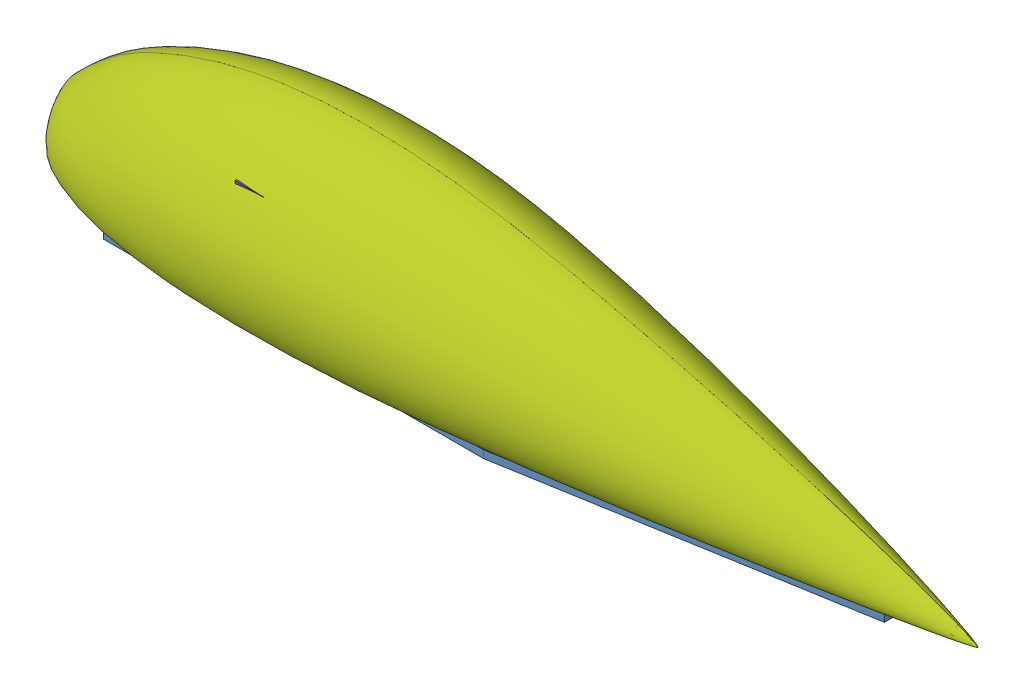
SolidWorks assembly full_vehicle, configuration Default. Lengths in mm.
Overall size (6096.03 1166.77 1555.25).
27 component instances, 15 part files, 32 mates.
Components (placement in the parent):
- sledFrame_003_rw-1: sledFrame_003_rw [Default] at (-4891.4665 1903.7696 4433.3238) size (5588 50.8 1016)
- drive_assembly-1: drive_assembly [Default] at (-3341.0425 1915.3862 4244.1915) x (0 0 1) z (-1 0 0) size (346.08 495.3 1111.25)
  - motor-1: motor [Default] at (4.9823 194.7584 300.6208) size (114.3 330.2 254)
  - drive_wheel-1: drive_wheel [Default] at (189.1323 143.9584 -16.8792) x (0 0 -1) z (1 0 0) size (304.8 304.8 101.6)
  - vertical_stability-1: vertical_stability [Default] at (189.1323 -124.9768 -16.8792) size (165.1 348.85 530.75)
  - drive_wheel-2: drive_wheel [Default] at (189.1323 143.9584 618.1208) x (0 0 1) z (-1 0 0) size (304.8 304.8 101.6)
  - vertical_stability-2: vertical_stability [Default] at (189.1323 -124.9768 618.1208) x (-1 0 0) z (0 0 -1) size (165.1 348.85 530.75)
  - Part1^drive_assembly-1: Part1^drive_assembly [Default] at (84.3573 143.9584 -16.8792) size (12.7 192.09 339.73) (virtual)
  - Part1^drive_assembly-2: Part1^drive_assembly [Default] at (281.2073 143.9584 -16.8792) size (12.7 192.09 339.73) (virtual)
  - Part1^drive_assembly-3: Part1^drive_assembly [Default] at (84.3573 143.9584 618.1208) size (12.7 192.09 339.73) (virtual)
  - Part1^drive_assembly-4: Part1^drive_assembly [Default] at (281.2073 143.9584 618.1208) size (12.7 192.09 339.73) (virtual)
- battery_pack-1: battery_pack [Default] at (-3018.7283 2021.2446 4823.2138) x (0 0 -1) z (1 0 0) size (134.62 152.4 1325.88)
- battery_pack-2: battery_pack [Default] at (-3018.7283 2021.2446 4043.4338) x (0 0 1) z (-1 0 0) size (134.62 152.4 1325.88)
- Body_006_rw-1: Body_006_rw [Default] at (-5653.4665 1954.5696 4433.3238) x (1 0 0.000021) z (-0.000021 0 1) size (6096 981.34 1555.12)
- radiator-1: radiator [Default] at (-3872.1683 2287.9446 3998.3488) x (-1 0 0) z (0 0 1) size (381 685.8 44.45)
- horizontal_stability-1: horizontal_stability [Default] at (-2876.2243 1919.6446 4433.3238) x (0 0 -1) z (1 0 0) size (307.09 115.06 127)
- horizontal_stability-2: horizontal_stability [Default] at (-4311.8611 1919.6446 4433.3238) x (0 0 -1) z (1 0 0) size (307.09 115.06 127)
- friction_brake-1: friction_brake [Default] at (-4777.1665 1901.7122 4404.7488) x (0 0 -1) z (1 0 0) size (107.95 142.42 127)
- friction_brake-2: friction_brake [Default] at (-4777.1665 1901.7122 4461.8988) x (0 0 1) z (-1 0 0) size (107.95 142.42 127)
- friction_brake-3: friction_brake [Default] at (-2451.0383 1901.7122 4404.7488) x (0 0 -1) z (1 0 0) size (107.95 142.42 127)
- friction_brake-4: friction_brake [Default] at (-2451.0383 1901.7122 4461.8988) x (0 0 1) z (-1 0 0) size (107.95 142.42 127)
- air_tank-1: air_tank [Default] at (-3359.7769 2030.7696 4686.1159) x (0 0 -1) z (1 0 0) size (152.4 152.4 279.4)
- compressor-1: compressor [Default] at (-2979.22 2008.5446 4702.3337) x (0 0 -1) z (1 0 0) size (127 127 254)
- radiator-2: radiator [Default] at (-3872.1683 2287.9446 4868.2988) x (-1 0 0) z (0 0 1) size (381 685.8 44.45)
- male95_scaled-1: male95_scaled [Default] at (-4390.3879 2202.234 4397.5196) x (-0.009816 -0.01136 0.999887) z (-0.756636 0.653836 0) size (328.47 766.25 480.34)
- pressure_vessel-1: pressure_vessel [Default] at (-5056.735 1954.5696 4433.3238) x (0 0 -1) z (1 0 0) size (457.2 508 1117.6)
- Seat assembly-3: Seat assembly [Default] at (-4400.9888 1860.8969 4286.9527) x (0 0 1) z (-1 0 0) size (311.15 341.17 561.02)
Mates (geometry in assembly coordinates):
- Drive Wheels and Sled Co-Planar: coincident aligned: plane of sledFrame_003_rw-1 through (-4891.4665 1903.7696 4433.3238) normal (0 0 1); plane of drive_assembly-1/drive_wheel-1 through (-3324.1633 2059.3446 4433.3238) normal (0 0 1)
- Motor Base and Beam 2 Co-Planar: coincident anti-aligned: plane of sledFrame_003_rw-1 through (-3625.7883 1945.0446 504433.3238) normal (0 1 0); plane of drive_assembly-1/motor-1 through (-3768.6633 1945.0446 4306.3238) normal (0 -1 0)
- Center Motor Over Beam 2: symmetric aligned: line of sledFrame_003_rw-1 through (-3657.5383 1945.0446 4890.5238) axis (0 0 -1); line of sledFrame_003_rw-1 through (-3625.7883 1945.0446 4890.5238) axis (0 0 -1); plane of drive_assembly-1/motor-1 through (-3641.6633 2110.1446 4249.1738) normal (-1 0 0)
- Battery Pack Vertical Position: coincident anti-aligned: plane of sledFrame_003_rw-1 through (-2355.7883 1945.0446 504433.3238) normal (0 1 0); plane of battery_pack-1 through (-2355.7883 1945.0446 4890.5238) normal (0 -1 0)
- Battery Pack Lateral Position: coincident anti-aligned: plane of sledFrame_003_rw-1 through (-4840.6665 1954.5696 4890.5238) normal (0 0 -1); plane of battery_pack-1 through (-2355.7883 1945.0446 4890.5238) normal (0 0 1)
- Battery Pack Forward Position: coincident aligned: plane of sledFrame_003_rw-1 through (-2355.7883 1945.0446 504433.3238) normal (1 0 0); plane of battery_pack-1 through (-2355.7883 2021.2446 4823.2138) normal (1 0 0)
- Aeroshell Vertical Position: coincident anti-aligned: plane of sledFrame_003_rw-1 through (-4891.4665 1954.5696 4433.3238) normal (0 1 0); plane of Body_006_rw-1 through (-5653.4665 1954.5696 4433.1968) normal (0 -1 0)
- Aeroshell Nose Fix: coincident: point of sledFrame_003_rw-1; point of Body_006_rw-1
- Aeroshell Plane Fix: tangent: plane of sledFrame_003_rw-1 through (-4891.4665 1903.7696 4433.3238) normal (0 0 1); curve of Body_006_rw-1
- HStab Centered on Vehicle: coincident anti-aligned: plane of sledFrame_003_rw-1 through (-4891.4665 1903.7696 4433.3238) normal (0 0 1); plane of horizontal_stability-1 through (-2876.2243 1919.6446 4433.3238) normal (0 0 -1)
- HStab Vertical Position: coincident aligned: plane of drive_assembly-1/vertical_stability-1 through (-3324.1633 1843.4446 4433.3238) normal (0 1 0); plane of horizontal_stability-1 through (-2876.2243 1843.4446 4433.3238) normal (0 1 0)
- HStab2 Vertical Position: coincident aligned: plane of horizontal_stability-1 through (-2876.2243 1843.4446 4433.3238) normal (0 1 0); plane of horizontal_stability-2 through (-4311.8611 1843.4446 4433.3238) normal (0 1 0)
- HStab2 Lateral Position: coincident aligned: plane of horizontal_stability-1 through (-2876.2243 1919.6446 4433.3238) normal (0 0 -1); plane of horizontal_stability-2 through (-4311.8611 1919.6446 4433.3238) normal (0 0 -1)
- Friction Brake I Beam Offset: distance = 3.175 mm anti-aligned: plane of drive_assembly-1/vertical_stability-2 through (-3959.0363 1906.9446 4369.8238) normal (0 0 -1); plane of friction_brake-1 through (-4840.6665 1895.3622 4366.6488) normal (0 0 1)
- Friction Brakes Vertical Position: symmetric aligned: plane of drive_assembly-1/vertical_stability-2 through (-3959.0363 1906.9446 4496.8238) normal (0 1 0); plane of drive_assembly-1/vertical_stability-2 through (-3959.0363 1896.4798 4369.8238) normal (0 -1 0); plane of friction_brake-1 through (-4777.1665 1901.7122 4404.7488) normal (0 1 0)
- Friction Brakes Forward Position: coincident anti-aligned: plane of sledFrame_003_rw-1 through (-4840.6665 1954.5696 3976.1238) normal (1 0 0); plane of friction_brake-1 through (-4840.6665 1932.3446 4404.7488) normal (-1 0 0)
- FB2 Vertical Position: coincident aligned: plane of friction_brake-1 through (-4777.1665 1901.7122 4404.7488) normal (0 1 0); plane of friction_brake-3 through (-2451.0383 1901.7122 4404.7488) normal (0 1 0)
- FB2 Lateral Position: coincident aligned: plane of friction_brake-1 through (-4777.1665 1901.7122 4404.7488) normal (0 0 -1); plane of friction_brake-3 through (-2451.0383 1901.7122 4404.7488) normal (0 0 -1)
- FB2 Forward Position: coincident anti-aligned: plane of sledFrame_003_rw-1 through (-2387.5383 1945.0446 504433.3238) normal (-1 0 0); plane of friction_brake-3 through (-2387.5383 1932.3446 4366.6488) normal (1 0 0)
- Air Tank Forward Orientation: parallel anti-aligned: plane of sledFrame_003_rw-1 through (-4891.4665 1903.7696 4433.3238) normal (0 0 1); plane of air_tank-1 through (-3359.7769 2030.7696 4686.1159) normal (0 0 -1)
- Air Tank Vertical Position: tangent anti-aligned: plane of sledFrame_003_rw-1 through (-4891.4665 1954.5696 4433.3238) normal (0 1 0); cylinder of air_tank-1 through (-3499.4769 2030.7696 4686.1159) axis (-1 0 0) radius 76.2
- Compressor Forward Orientation: parallel anti-aligned: plane of sledFrame_003_rw-1 through (-4891.4665 1903.7696 4433.3238) normal (0 0 1); plane of compressor-1 through (-2979.22 2008.5446 4702.3337) normal (0 0 -1)
- Compressor Vertical Position: coincident anti-aligned: plane of sledFrame_003_rw-1 through (-3625.7883 1945.0446 504433.3238) normal (0 1 0); plane of compressor-1 through (-2852.22 1945.0446 4765.8337) normal (0 -1 0)
- Pressure Vessel Vertical Position: coincident anti-aligned: plane of sledFrame_003_rw-1 through (-4891.4665 1954.5696 4433.3238) normal (0 1 0); plane of pressure_vessel-1 through (-4726.535 1954.5696 4433.3238) normal (0 -1 0)
- Pressure Vessel Aligned with Centerline: coincident anti-aligned: plane of sledFrame_003_rw-1 through (-4891.4665 1903.7696 4433.3238) normal (0 0 1); plane of pressure_vessel-1 through (-5056.735 1954.5696 4433.3238) normal (0 0 -1)
- Radiator Lateral Position: coincident aligned: plane of battery_pack-2 through (-3681.6683 1945.0446 3976.1238) normal (0 0 -1); plane of radiator-1 through (-3872.1683 2287.9446 3976.1238) normal (0 0 -1)
- Radiator Forward Position: coincident anti-aligned: plane of battery_pack-2 through (-3681.6683 2021.2446 4043.4338) normal (-1 0 0); plane of radiator-1 through (-3681.6683 2630.8446 4020.5738) normal (1 0 0)
- Radiator Vertical Position: coincident aligned: plane of battery_pack-2 through (-3681.6683 1945.0446 3976.1238) normal (0 -1 0); plane of radiator-1 through (-3681.6683 1945.0446 4020.5738) normal (0 -1 0)
- Chair on Bottom of Pressure Vessel: coincident anti-aligned: plane of pressure_vessel-1 through (-4726.535 1967.2696 4433.3238) normal (0 1 0); plane of Seat assembly-3 through (-4802.5665 1967.2696 4331.7238) normal (0 -1 0)
- Chair Midplane: coincident aligned: plane of sledFrame_003_rw-1 through (-4891.4665 1903.7696 4433.3238) normal (0 0 1); plane of Seat assembly-3 through (-4400.9888 1860.8969 4433.3238) normal (0 0 1)
- Distance1: distance = 76.2 mm aligned: plane of Seat assembly-3 through (-4815.2665 2030.7696 4331.7238) normal (-1 0 0); plane of sledFrame_003_rw-1 through (-4891.4665 1954.5696 3925.3238) normal (-1 0 0)
- Coincident20: coincident anti-aligned: plane of male95_scaled-1 through (-4487.8127 2138.3468 4429.9838) normal (0.756636 -0.653836 0); plane of Seat assembly-3 through (-4589.5378 2020.6279 4522.2238) normal (-0.756636 0.653836 0)
